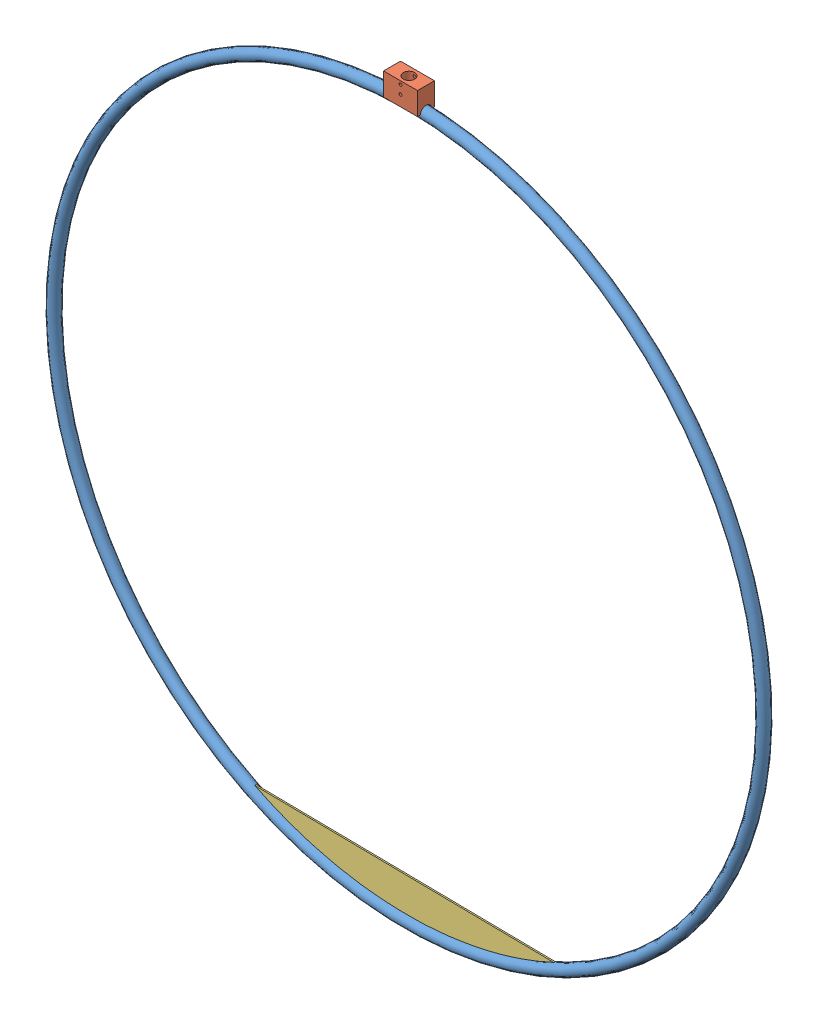
SolidWorks assembly Assem2, configuration Default. Lengths in mm.
Overall size (1617.6 1655.7 38.1).
3 component instances, 3 part files, 9 mates.
Components (placement in the parent):
- Ring-1: Ring [Default] at (0 808.7995 0) x (0 0 -1) z (-1 0 0) size (25.4 1617.6 1617.6)
- SupportBlock-1: SupportBlock [Default] at (-38.1 1630.299 0) x (0 0 -1) z (1 0 0) size (38.1 51.94 76.2)
- Elec Board-1: Elec Board [Default] at (-344.2695 105.9652 -1.6002) x (0.99992 -0.012661 0) z (0 0 1) size (670.56 76.2 3.2)
Mates (geometry in assembly coordinates):
- Tangent8: tangent: torus of Ring-1; plane of assembly through (0 0 0) normal (0 1 0)
- Coincident15: coincident anti-aligned: plane of Ring-1; plane of assembly through (0 0 0) normal (0 0 1)
- Coincident16: coincident anti-aligned: plane of Ring-1 through (0 808.7995 0) normal (-1 0 0); plane of assembly through (0 0 0) normal (1 0 0)
- Symmetric1: symmetric aligned: plane of SupportBlock-1 through (38.1 1655.699 19.05) normal (0 0 1); plane of SupportBlock-1 through (38.1 1655.699 -19.05) normal (0 0 -1); plane of assembly through (0 0 0) normal (0 0 1)
- Parallel1: parallel aligned: plane of assembly through (0 0 0) normal (0 1 0); plane of SupportBlock-1 through (38.1 1655.699 19.05) normal (0 1 0)
- Symmetric2: symmetric aligned: plane of Ring-1 through (0 808.7995 0) normal (-1 0 0); plane of SupportBlock-1 through (-38.1 1630.299 0) normal (-1 0 0); plane of SupportBlock-1 through (38.1 1630.299 0) normal (1 0 0)
- Tangent10: tangent: torus of Ring-1; cylinder of SupportBlock-1 through (38.1 1604.899 0) axis (-1 0 0) radius 12.7
- Symmetric3: symmetric aligned: plane of Elec Board-1 through (3.5965 807.8231 -1.6002) normal (0 0 -1); plane of Elec Board-1 through (3.5965 807.8231 1.6002) normal (0 0 1); plane of assembly through (0 0 0) normal (0 0 1)
- Tangent11: tangent: torus of Ring-1; cylinder of Elec Board-1 through (-0.0635 808.7996 1.6002) axis (0 0 -1) radius 783.336
